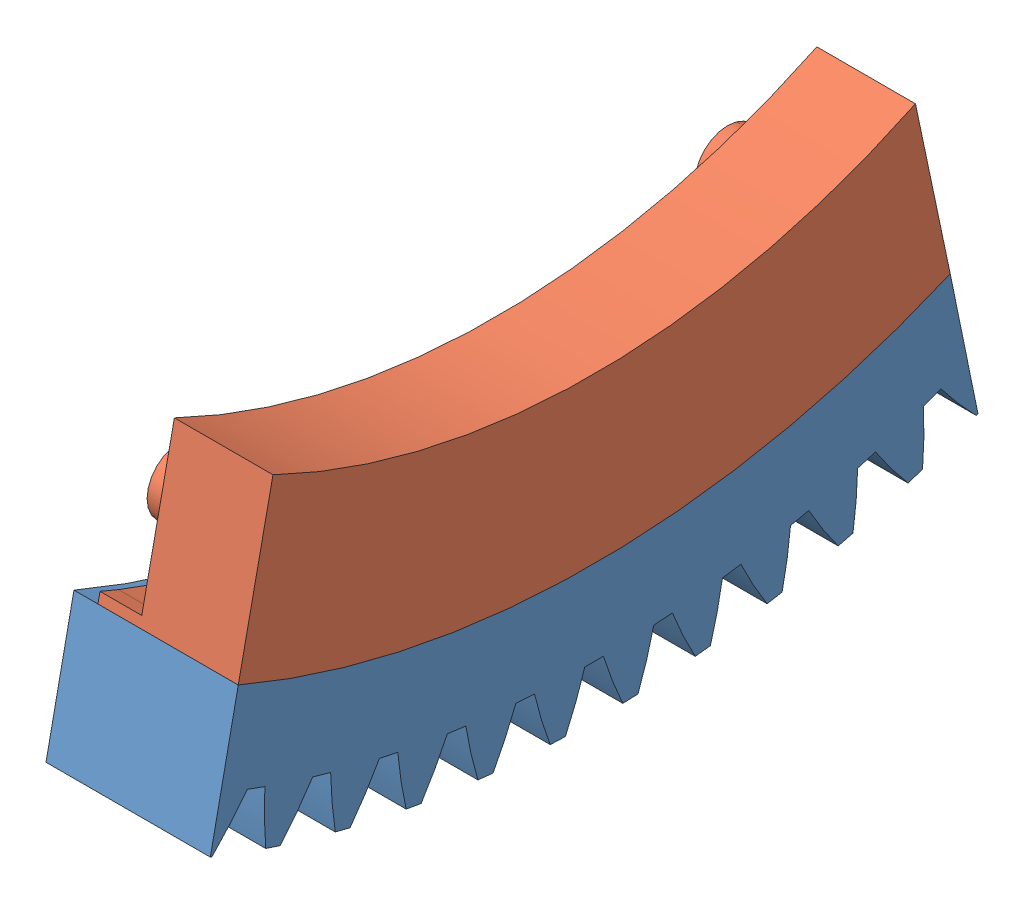
SolidWorks assembly gear_attach2, configuration Default. Lengths in mm.
Overall size (10 22.7 46.72).
2 component instances, 2 part files, 3 mates.
Components (placement in the parent):
- Metric - Spur gear 1.375M 90T 20PA 10FW ---S90O75H50L110N-1: Metric - Spur gear 1.375M 90T 20PA 10FW ---S90O75H50L110N [Metric - Spur gear 1.375M 90T 20PA 10FW ---S90O75H50L110N] at (-1.8854 10.4513 -8.744) size (10 126.45 126.5)
- 3d_extend-1: 3d_extend [Default] at (8.1146 10.4513 -8.744) x (0 0 1) z (-1 0 0) size (43.33 14.47 8.54)
Mates (geometry in assembly coordinates):
- Coincident1: coincident: plane of Metric - Spur gear 1.375M 90T 20PA 10FW ---S90O75H50L110N-1 through (8.1146 10.4513 -8.744) normal (1 0 0); plane of 3d_extend-1 through (8.1146 10.4513 -8.744) normal (1 0 0)
- Coincident2: coincident: line of Metric - Spur gear 1.375M 90T 20PA 10FW ---S90O75H50L110N-1 through (8.1146 -40.1002 -30.4131) axis (-1 0 0); line of 3d_extend-1 through (-0.4254 -40.1002 -30.4131) axis (1 0 0)
- Coincident3: coincident anti-aligned: line of Metric - Spur gear 1.375M 90T 20PA 10FW ---S90O75H50L110N-1 through (8.1146 -40.1056 12.9125) axis (-1 0 0); line of 3d_extend-1 through (-0.4254 -40.1056 12.9125) axis (1 0 0)
